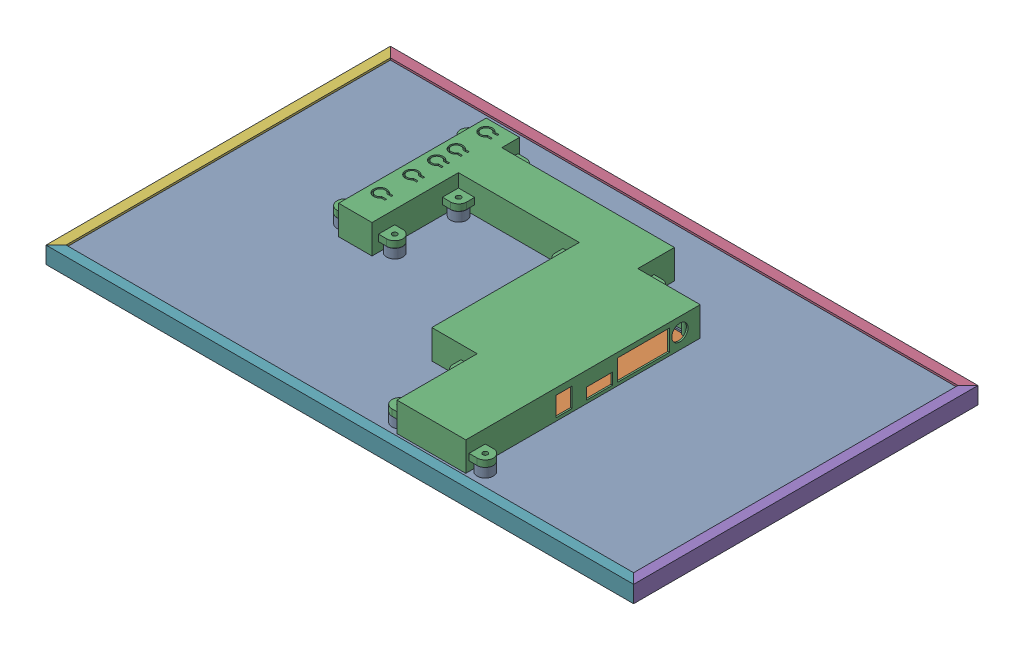
SolidWorks assembly Assem, configuration Default. Lengths in mm.
Overall size (362.4 26.6 212.4).
7 component instances, 5 part files, 29 mates.
Components (placement in the parent):
- back_cover_part-1: back_cover_part [Default] at (46.1111 49.7795 141.8319) size (360 6.7 210)
- display_part-1: display_part [Default] at (46.1111 49.7795 141.8319) x (-1 0 0) z (0 0 1) size (360 7 210)
- display_support_part-1: display_support_part [Default] at (46.1306 50.6795 187.2998) x (1 0 0.000437) z (-0.000437 0 1) size (185.65 18 178.1)
- long_frame_part-1: long_frame_part [Default] at (46.1111 47.2795 36.8319) x (1 0 0) z (0 -1 0) size (362.4 6.2 10.4)
- short_frame_part-1: short_frame_part [Default] at (226.1111 47.2795 141.8319) x (0 0 -1) z (0 1 0) size (212.4 6.2 10.4)
- short_frame_part-2: short_frame_part [Default] at (-133.8889 47.2795 141.8319) x (0 0 1) z (0 1 0) size (212.4 6.2 10.4)
- long_frame_part-2: long_frame_part [Default] at (46.1111 47.2795 246.8319) x (1 0 0) z (0 1 0) size (362.4 6.2 10.4)
Mates (geometry in assembly coordinates):
- Concentric1: concentric aligned: circle of back_cover_part-1; circle of display_support_part-1
- Concentric5: concentric: circle of back_cover_part-1; circle of display_support_part-1
- Parallel1: parallel anti-aligned: plane of back_cover_part-1 through (46.1111 50.7795 141.8319) normal (0 1 0); plane of display_support_part-1 through (46.1306 50.6795 187.2998) normal (0 -1 0)
- Parallel2: parallel anti-aligned: plane of back_cover_part-1 through (46.1111 49.7795 141.8319) normal (0 -1 0); plane of display_part-1 through (46.1111 49.7795 141.8319) normal (0 1 0)
- Parallel3: parallel anti-aligned: plane of back_cover_part-1 through (46.1111 49.7795 141.8319) normal (0 -1 0); plane of display_part-1 through (46.1111 49.7795 141.8319) normal (0 1 0)
- Distance2: distance = 0 mm anti-aligned: plane of display_part-1 through (46.1111 49.7795 141.8319) normal (0 1 0); plane of back_cover_part-1 through (46.1111 49.7795 141.8319) normal (0 -1 0)
- Parallel4: parallel aligned: line of back_cover_part-1 through (226.1111 50.7795 246.8319) axis (-1 0 0); line of display_part-1 through (226.1111 49.7795 246.8319) axis (-1 0 0)
- Parallel5: parallel aligned: line of back_cover_part-1 through (226.1111 49.7795 246.8319) axis (0 0 -1); line of display_part-1 through (226.1111 49.7795 246.8319) axis (0 0 -1)
- Distance3: distance = 0 mm: line of display_part-1 through (226.1111 49.7795 246.8319) axis (0 0 -1); line of back_cover_part-1 through (226.1111 49.7795 246.8319) axis (0 0 -1)
- Distance4: distance = 0 mm: line of back_cover_part-1 through (226.1111 49.7795 246.8319) axis (-1 0 0); line of display_part-1 through (226.1111 49.7795 246.8319) axis (-1 0 0)
- Parallel7: parallel anti-aligned: plane of display_part-1 through (46.1111 43.2795 246.8319) normal (0 0 1); plane of long_frame_part-2 through (227.3111 51.2795 246.8319) normal (0 0 -1)
- Distance5: distance = 0 mm anti-aligned: plane of long_frame_part-2 through (227.3111 51.2795 246.8319) normal (0 0 -1); plane of display_part-1 through (46.1111 43.2795 246.8319) normal (0 0 1)
- Distance6: distance = 0 mm anti-aligned: plane of long_frame_part-2 through (227.3111 43.2795 246.8319) normal (0 1 0); plane of display_part-1 through (46.1111 43.2795 141.8319) normal (0 -1 0)
- Distance7: distance = 0 mm: line of display_part-1 through (226.1111 43.2795 246.8319) axis (0 1 0); line of long_frame_part-2 through (226.1111 51.2795 246.8319) axis (0 -1 0)
- Parallel8: parallel anti-aligned: plane of display_part-1 through (46.1111 43.2795 36.8319) normal (0 0 -1); plane of long_frame_part-1 through (227.3111 43.2795 36.8319) normal (0 0 1)
- Distance9: distance = 0 mm anti-aligned: plane of display_part-1 through (46.1111 43.2795 36.8319) normal (0 0 -1); plane of long_frame_part-1 through (227.3111 43.2795 36.8319) normal (0 0 1)
- Distance10: distance = 0 mm anti-aligned: plane of long_frame_part-1 through (227.3111 43.2795 41.8319) normal (0 1 0); plane of display_part-1 through (46.1111 43.2795 141.8319) normal (0 -1 0)
- Distance11: distance = 0 mm: line of long_frame_part-1 through (-133.8889 51.2795 36.8319) axis (0 -1 0); line of display_part-1 through (-133.8889 43.2795 36.8319) axis (0 1 0)
- Parallel9: parallel anti-aligned: plane of display_part-1 through (-133.8889 43.2795 141.8319) normal (-1 0 0); plane of short_frame_part-2 through (-133.8889 51.2795 248.0319) normal (1 0 0)
- Parallel10: parallel anti-aligned: line of long_frame_part-1 through (-135.0889 42.0795 35.6319) axis (0 1 0); line of short_frame_part-2 through (-135.0889 52.4795 35.6319) axis (0 -1 0)
- Distance12: distance = 0 mm anti-aligned: plane of short_frame_part-2 through (-133.8889 51.2795 248.0319) normal (1 0 0); plane of display_part-1 through (-133.8889 43.2795 141.8319) normal (-1 0 0)
- Distance13: distance = 0 mm anti-aligned: plane of short_frame_part-2 through (-133.8889 43.2795 248.0319) normal (0 1 0); plane of display_part-1 through (46.1111 43.2795 141.8319) normal (0 -1 0)
- Distance14: distance = 0 mm: line of short_frame_part-2 through (-135.0889 52.4795 35.6319) axis (0 -1 0); line of long_frame_part-1 through (-135.0889 42.0795 35.6319) axis (0 1 0)
- Parallel11: parallel anti-aligned: plane of display_part-1 through (226.1111 43.2795 141.8319) normal (1 0 0); plane of short_frame_part-1 through (226.1111 51.2795 35.6319) normal (-1 0 0)
- Parallel12: parallel anti-aligned: line of long_frame_part-1 through (227.3111 42.0795 35.6319) axis (0 1 0); line of short_frame_part-1 through (227.3111 52.4795 248.0319) axis (0 -1 0)
- Distance16: distance = 0 mm anti-aligned: plane of short_frame_part-1 through (226.1111 43.2795 35.6319) normal (0 1 0); plane of display_part-1 through (46.1111 43.2795 141.8319) normal (0 -1 0)
- Distance17: distance = 0 mm anti-aligned: plane of display_part-1 through (226.1111 43.2795 141.8319) normal (1 0 0); plane of short_frame_part-1 through (226.1111 51.2795 35.6319) normal (-1 0 0)
- Distance18: distance = 0 mm: line of long_frame_part-2 through (227.3111 52.4795 248.0319) axis (0 -1 0); line of short_frame_part-1 through (227.3111 52.4795 248.0319) axis (0 -1 0)
- LimitDistance1: limit distance = 0 mm anti-aligned: plane of display_support_part-1 through (46.1306 56.4795 187.2998) normal (0 -1 0); plane of back_cover_part-1 through (-25.2889 56.4795 142.7319) normal (0 1 0)
